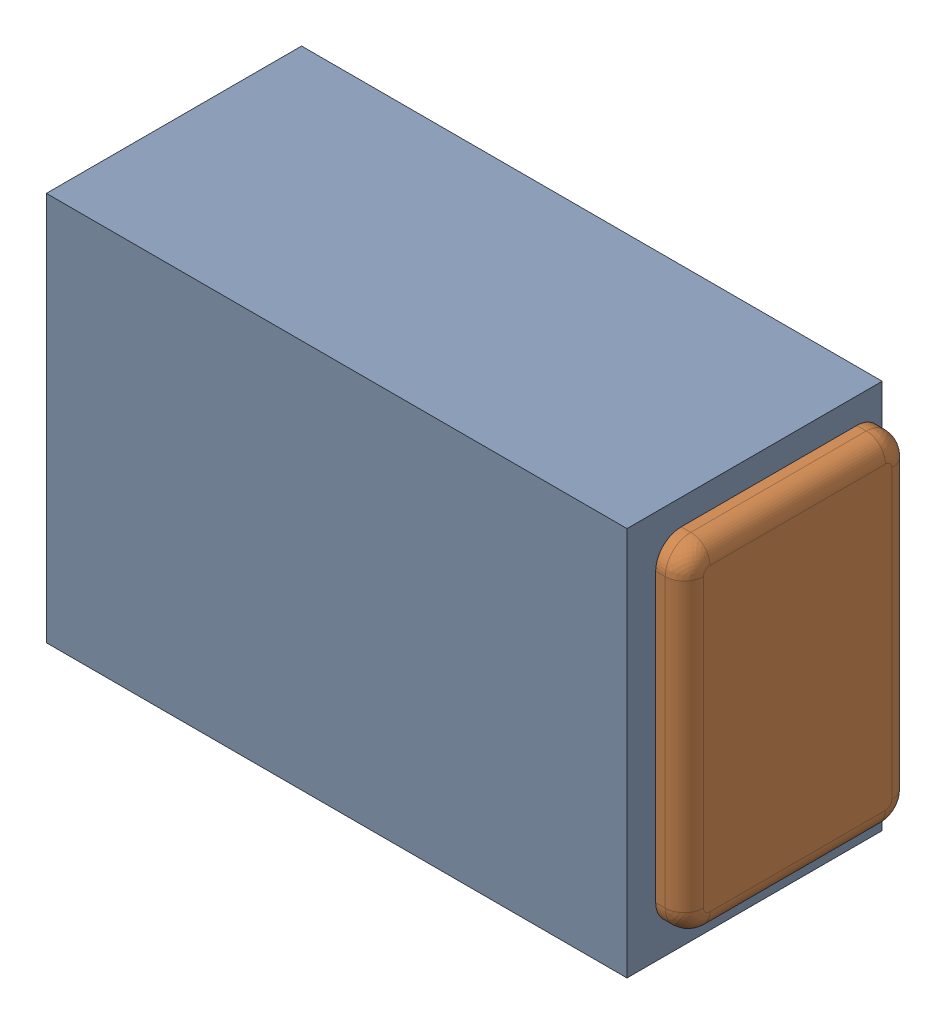
SolidWorks assembly C20, configuration Default. Lengths in mm.
Overall size (1 0.61 0.4).
3 component instances, 2 part files, 0 mates.
Components (placement in the parent):
- 1088880352-1: 1088880352 [Default] at (10.925 7.525 0) size (0.91 0.61 0.4)
  - Extruded-28-1: Extruded-28 [Default] at origin size (0.91 0.61 0.4)
- C0402-1: C0402 [Default] at (10.9249 7.5249 0) x (-1 0 0) z (0 1 0) size (1 0.36 0.54)
